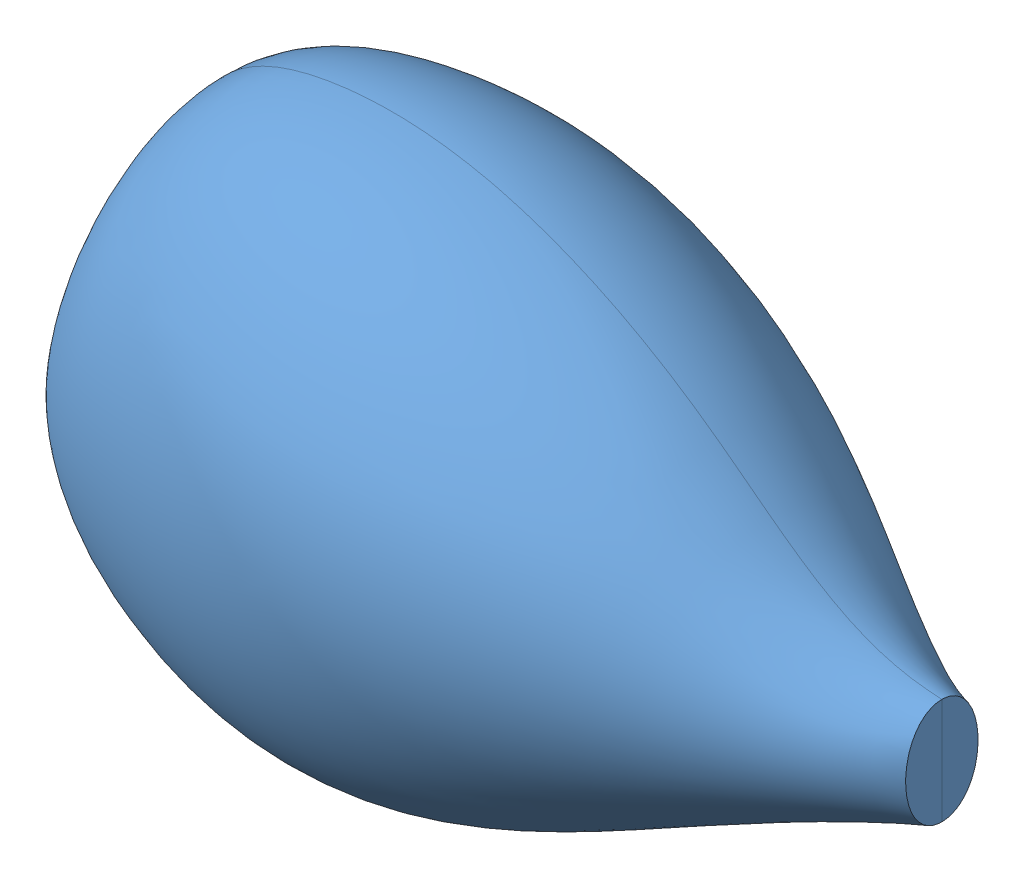
SolidWorks assembly Assem1, configuration Default. Lengths in mm.
Overall size (109.1 76.99 56.5).
62 component instances, 17 part files, 2 mates.
Components (placement in the parent):
- BodySmall-1: BodySmall [Default] at (-14.6171 31.7612 0) size (109.1 76.99 56.5)
- MicroServo-1: MicroServo [Default] at (41.6207 40.8927 0) x (0 -1 0) z (0 0 1) size (40.02 29.7 12.14)
- ASSEMBLY-1: ASSEMBLY [Default] at (-4.9344 45.3921 15.3329) x (0 0 -1) z (1 0 0) size (17.78 12.75 33.02)
  - board-1: board [Default] at (5.4752 15.0552 41.6975) size (17.78 1.67 33.02)
  - ATmega-1: ATmega [Default] at (14.3652 16.8027 27.7275) x (0.707107 0 0.707107) z (-0.707107 0 0.707107) size (9 1.1 9)
  - cap_603-1: cap_603 [Default] at (10.3417 16.7052 40.4401) x (0 0 -1) z (1 0 0) size (1.6 0.8 0.8)
  - cap_603-2: cap_603 [Default] at (13.6922 16.7052 34.8585) size (1.6 0.8 0.8)
  - cap_603-3: cap_603 [Default] at (11.8634 16.7052 21.6759) size (1.6 0.8 0.8)
  - cap_603-4: cap_603 [Default] at (17.4768 16.7052 12.8875) size (1.6 0.8 0.8)
  - res_603-1: res_603 [Default] at (10.4218 16.7052 37.2651) x (0 0 -1) z (1 0 0) size (1.6 0.5 0.8)
  - res_603-2: res_603 [Default] at (19.5912 16.7052 37.5953) x (0 0 -1) z (1 0 0) size (1.6 0.5 0.8)
  - res_603-3: res_603 [Default] at (15.1652 16.7052 14.6275) x (-1 0 0) z (0 0 -1) size (1.6 0.5 0.8)
  - condensateurTantale_106C-1: condensateurTantale_106C [Défaut] at (10.1742 17.5052 15.6625) x (0 0 -1) z (1 0 0) size (3.2 1.6 1.6)
  - condensateurTantale_106C-2: condensateurTantale_106C [Défaut] at (18.6832 17.5052 17.5675) x (0 0 -1) z (1 0 0) size (3.2 1.6 1.6)
  - SOT23-5-1: SOT23-5 [Default] at (14.3653 16.6848 17.5167) x (1 0 0) z (0 1 0) size (2.91 3.01 1.23)
  - Surface Mount Chip LED 3.2x1.6mm-1: Surface Mount Chip LED 3.2x1.6mm [Default] at (18.7112 16.7112 39.0103) x (0 0 1) z (0 1 0) size (1.92 0.96 0.72)
  - Surface Mount Chip LED 3.2x1.6mm-2: Surface Mount Chip LED 3.2x1.6mm [Default] at (13.4306 16.7112 20.3081) x (1 0 0) z (0 1 0) size (1.92 0.96 0.72)
  - Crystal_Low_Profile-1: Crystal_Low_Profile [Default] at (9.717 16.7052 22.6754) x (0 0 -1) z (0 1 0) size (3.84 1.66 0.85)
    - Fusion001-1: Fusion001 [Default] at origin size (3.84 1.66 0.85)
  - TACTILE-SWITCH-SMD-ALT01-1: TACTILE-SWITCH-SMD-ALT01 [Default] at (14.4922 16.7052 39.0305) size (6.4 1.4 5.25)
  - Pin Header 1x12 TH Pitch 2.54mm-1: Pin Header 1x12 TH Pitch 2.54mm [Default] at (6.7452 15.0555 40.428) x (0 0.000074 -1) z (0 -1 -0.000074) size (30.48 2.54 12.7)
  - Pin Header 1x12 TH Pitch 2.54mm-2: Pin Header 1x12 TH Pitch 2.54mm [Default] at (21.9852 15.0555 40.428) x (0 0.000074 -1) z (0 -1 -0.000074) size (30.48 2.54 12.7)
  - Pin Header 1x2 TH Pitch 2.54mm-1: Pin Header 1x2 TH Pitch 2.54mm [Default] at (19.0642 15.0566 31.6645) x (0 0 1) z (0 -1 0) size (5.08 2.54 12.7)
  - Pin Header 1x2 TH Pitch 2.54mm-2: Pin Header 1x2 TH Pitch 2.54mm [Default] at (19.0642 15.0565 21.2505) x (0 0.000074 1) z (0 -1 0.000074) size (5.08 2.54 12.7)
  - Pin Header 1x6 TH Pitch 2.54mm-1: Pin Header 1x6 TH Pitch 2.54mm [Default] at (8.0152 15.0566 9.9475) x (1 0 0) z (0 -1 0) size (15.24 2.54 12.7)
  - solder-1: solder [Default] at (6.7452 16.7152 40.4275) size (1.8 1.45 1.8)
  - solder-13: solder [Default] at (21.9852 16.7152 40.4275) size (1.8 1.45 1.8)
  - solder-25: solder [Default] at (19.0642 16.7152 23.7905) size (1.8 1.45 1.8)
  - solder-37: solder [Default] at (19.0642 16.7152 34.2045) size (1.8 1.45 1.8)
  - solder-39: solder [Default] at (20.7152 16.7152 9.9475) size (1.8 1.45 1.8)
  - solder-2: solder [Default] at (6.7452 16.7152 37.8875) size (1.8 1.45 1.8)
  - solder-3: solder [Default] at (6.7452 16.7152 35.3475) size (1.8 1.45 1.8)
  - solder-4: solder [Default] at (6.7452 16.7152 32.8075) size (1.8 1.45 1.8)
  - solder-5: solder [Default] at (6.7452 16.7152 30.2675) size (1.8 1.45 1.8)
  - solder-6: solder [Default] at (6.7452 16.7152 27.7275) size (1.8 1.45 1.8)
  - solder-7: solder [Default] at (6.7452 16.7152 25.1875) size (1.8 1.45 1.8)
  - solder-8: solder [Default] at (6.7452 16.7152 22.6475) size (1.8 1.45 1.8)
  - solder-9: solder [Default] at (6.7452 16.7152 20.1075) size (1.8 1.45 1.8)
  - solder-10: solder [Default] at (6.7452 16.7152 17.5675) size (1.8 1.45 1.8)
  - solder-11: solder [Default] at (6.7452 16.7152 15.0275) size (1.8 1.45 1.8)
  - solder-12: solder [Default] at (6.7452 16.7152 12.4875) size (1.8 1.45 1.8)
  - solder-14: solder [Default] at (21.9852 16.7152 37.8875) size (1.8 1.45 1.8)
  - solder-15: solder [Default] at (21.9852 16.7152 35.3475) size (1.8 1.45 1.8)
  - solder-16: solder [Default] at (21.9852 16.7152 32.8075) size (1.8 1.45 1.8)
  - solder-17: solder [Default] at (21.9852 16.7152 30.2675) size (1.8 1.45 1.8)
  - solder-18: solder [Default] at (21.9852 16.7152 27.7275) size (1.8 1.45 1.8)
  - solder-19: solder [Default] at (21.9852 16.7152 25.1875) size (1.8 1.45 1.8)
  - solder-20: solder [Default] at (21.9852 16.7152 22.6475) size (1.8 1.45 1.8)
  - solder-21: solder [Default] at (21.9852 16.7152 20.1075) size (1.8 1.45 1.8)
  - solder-22: solder [Default] at (21.9852 16.7152 17.5675) size (1.8 1.45 1.8)
  - solder-23: solder [Default] at (21.9852 16.7152 15.0275) size (1.8 1.45 1.8)
  - solder-24: solder [Default] at (21.9852 16.7152 12.4875) size (1.8 1.45 1.8)
  - solder-26: solder [Default] at (19.0642 16.7152 21.2505) size (1.8 1.45 1.8)
  - solder-38: solder [Default] at (19.0642 16.7152 31.6645) size (1.8 1.45 1.8)
  - solder-40: solder [Default] at (18.1752 16.7152 9.9475) size (1.8 1.45 1.8)
  - solder-41: solder [Default] at (15.6352 16.7152 9.9475) size (1.8 1.45 1.8)
  - solder-42: solder [Default] at (13.0952 16.7152 9.9475) size (1.8 1.45 1.8)
  - solder-43: solder [Default] at (10.5552 16.7152 9.9475) size (1.8 1.45 1.8)
  - solder-44: solder [Default] at (8.0152 16.7152 9.9475) size (1.8 1.45 1.8)
- Battery2S-2: Battery2S [Default] at (30.8467 37.9196 8.4587) x (0.999956 -0.003479 -0.008756) z (-0.003629 -0.999848 -0.017071) size (60 8 19)
- Battery2S-3: Battery2S [Default] at (30.8467 37.9196 -8.4587) x (0.999956 -0.003479 0.008756) z (0.003629 0.999848 -0.017071) size (60 8 19)
- nRF24L01+_enhanced-1: nRF24L01+_enhanced [Default<As Machined>] at (-1.0539 34.9464 5.6864) x (0.021818 0.968111 0.249571) z (0.050669 -0.25038 0.966821) size (29 12.85 15)
Mates (geometry in assembly coordinates):
- Coincident1: coincident aligned: plane of MicroServo-1 through (41.6207 40.8927 0) normal (0 0 1); plane of assembly through (0 0 0) normal (0 0 1)
- Coincident2: coincident anti-aligned: plane of BodySmall-1 through (-14.6171 31.7612 0) normal (0 0 -1); plane of assembly through (0 0 0) normal (0 0 1)
